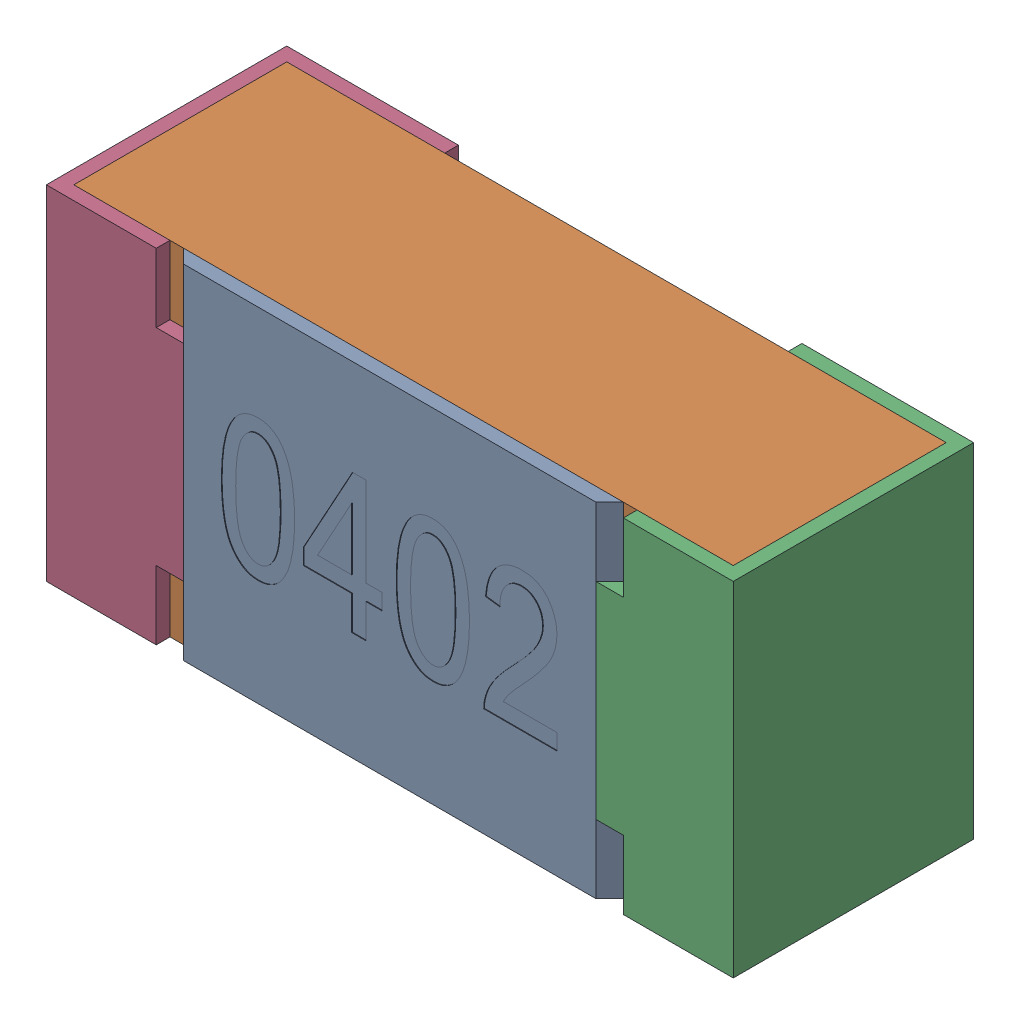
SolidWorks assembly R33, configuration Standard. Lengths in mm.
Overall size (1 0.5 0.35).
5 component instances, 4 part files, 0 mates.
Components (placement in the parent):
- R33-subassembly-1-1: R33-subassembly-1 [Standard] at (8.6001 -14.9 0) x (1 0 0) z (0 0 1) size (1 0.5 0.35)
  - User Library-R_0402-1: User Library-R_0402 [Standard] at origin size (0.64 0.5 0.02)
  - User Library-R_0402-1-1: User Library-R_0402-1 [Standard] at origin size (0.96 0.5 0.31)
  - User Library-R_0402-2-1: User Library-R_0402-2 [Standard] at origin size (0.25 0.5 0.35)
  - User Library-R_0402-3-1: User Library-R_0402-3 [Standard] at origin size (0.25 0.5 0.35)
